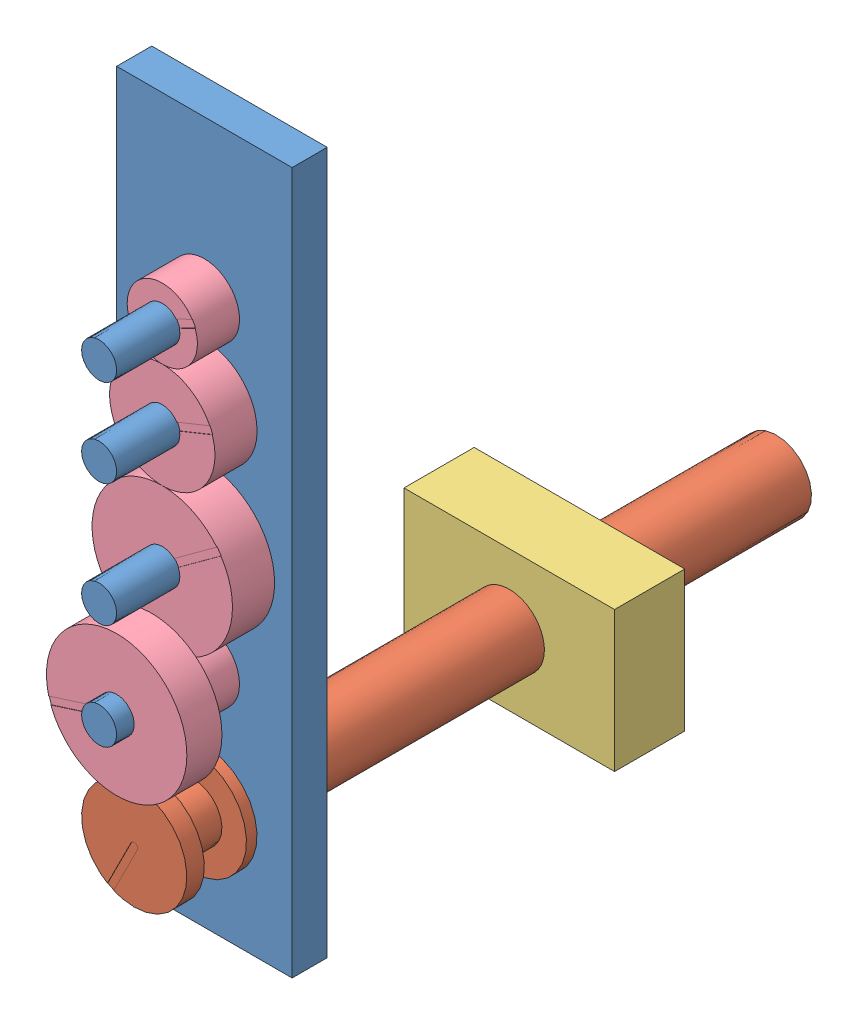
SolidWorks assembly test pignons, configuration Défaut. Lengths in mm.
Overall size (60 200 193).
7 component instances, 4 part files, 12 mates.
Components (placement in the parent):
- Pièce1^test pignons-1: Pièce1^test pignons [DEFAUT] at origin size (50 200 40) (virtual)
- Pièce2^test pignons-1: Pièce2^test pignons [DEFAUT] at (0 0 20) x (-0.893011 0.450035 0) z (0 0 1) size (30 30 183) (virtual)
- Pièce3^test pignons-1: Pièce3^test pignons [DEFAUT] at (0 0 -96.8807) size (60 40 20) (virtual)
- Pièce4^test pignons-2: Pièce4^test pignons [4] at (0 35 0) x (-0.302277 0.95322 0) z (0 0 1) size (40 40 25) (virtual)
- Pièce4^test pignons-3: Pièce4^test pignons [3] at (0 65 0) x (0.590645 -0.806931 0) z (0 0 1) size (40 40 12) (virtual)
- Pièce4^test pignons-4: Pièce4^test pignons [2] at (0 100 0) x (0.374903 -0.927064 0) z (0 0 1) size (30 30 12) (virtual)
- Pièce4^test pignons-5: Pièce4^test pignons [1] at (0 125 0) x (0.442145 -0.896943 0) z (0 0 1) size (20 20 12) (virtual)
Mates (geometry in assembly coordinates):
- Coïncidente1: coincident anti-aligned: circle of Pièce1^Assemblage1-1; circle of Pièce2^Assemblage1-1
- Coaxiale1: concentric aligned: cylinder of Pièce2^Assemblage1-1 through (0 0 -163) axis (0 0 -1) radius 10; cylinder of Pièce3^Assemblage1-1 through (0 0 -86.8807) axis (0 0 -1) radius 10
- Parallèle1: parallel aligned: plane of Pièce1^Assemblage1-1 through (25 170 -10) normal (1 0 0); plane of Pièce3^Assemblage1-1 through (30 20 -86.8807) normal (1 0 0)
- Hélicoïdale1: screw = 1 mm aligned: cylinder of Pièce2^Assemblage1-1 through (0 0 -163) axis (0 0 -1) radius 10; cylinder of Pièce3^Assemblage1-1 through (0 0 -86.8807) axis (0 0 -1) radius 10
- Coïncidente2: coincident aligned: circle of Pièce1^Assemblage1-1; circle of Pièce4^Assemblage1-2
- Coïncidente3: coincident aligned: circle of Pièce1^Assemblage1-1; circle of Pièce4^Assemblage1-3
- Coïncidente4: coincident aligned: circle of Pièce1^Assemblage1-1; circle of Pièce4^Assemblage1-4
- Coïncidente5: coincident aligned: circle of Pièce1^Assemblage1-1; circle of Pièce4^Assemblage1-5
- Contr.Engrenages1: gear = 30 : 20 mm: cylinder of Pièce4^Assemblage1-5 through (0 125 12) axis (0 0 -1) radius 10; cylinder of Pièce4^Assemblage1-4 through (0 100 12) axis (0 0 -1) radius 15
- Contr.Engrenages2: gear = 40 : 30 mm: cylinder of Pièce4^Assemblage1-4 through (0 100 12) axis (0 0 -1) radius 15; cylinder of Pièce4^Assemblage1-3 through (0 65 12) axis (0 0 -1) radius 20
- Contr.Engrenages3: gear = 20 : 40 mm: cylinder of Pièce4^Assemblage1-3 through (0 65 12) axis (0 0 -1) radius 20; cylinder of Pièce4^Assemblage1-2 through (0 35 15) axis (0 0 -1) radius 10
- Contr.Engrenages4: gear = 30 : 40 mm: cylinder of Pièce4^Assemblage1-2 through (0 35 25) axis (0 0 -1) radius 20; cylinder of Pièce2^Assemblage1-1 through (0 0 -163) axis (0 0 -1) radius 15
